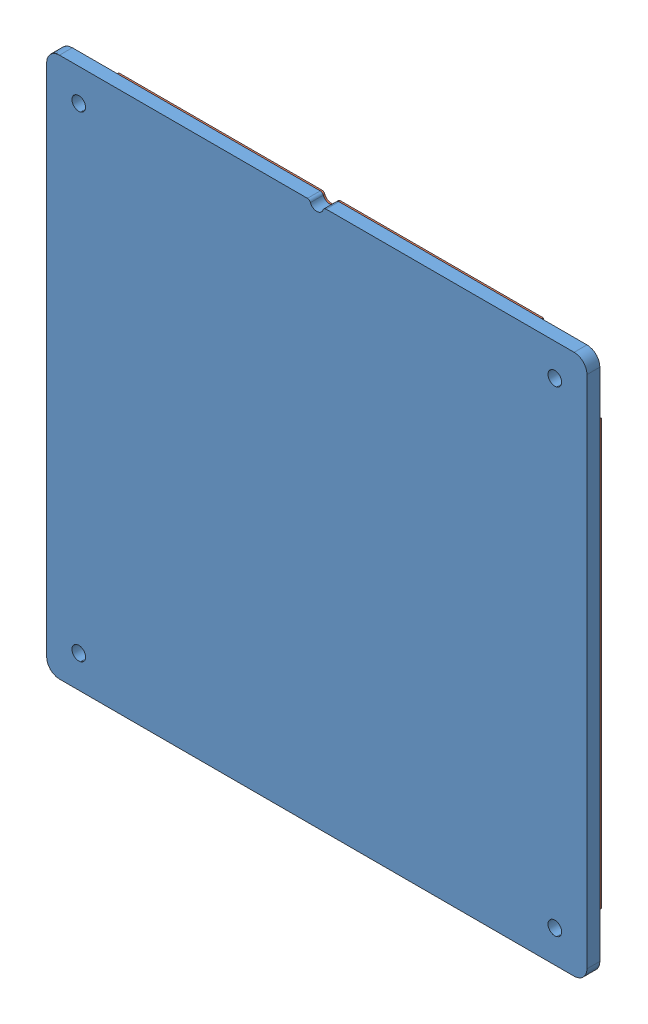
SolidWorks assembly FE-00083, configuration FE-00083-ID6. Lengths in mm.
Overall size (266.7 266.7 7.11).
2 component instances, 2 part files, 5 mates.
Components (placement in the parent):
- FE-00082-1: FE-00082 [Default] at (0 0 0.762) size (266.7 266.7 6.35)
- FE-00083-Vinyl-2: FE-00083-Vinyl [FE-00083-ID6-Vinyl] at (0 0 6.35) x (-1 0 0) z (0 0 -1) size (266.7 266.7 6.35)
Mates (geometry in assembly coordinates):
- Coincident5: coincident aligned: plane of FE-00082-1 through (133.35 -133.35 7.112) normal (1 0 0); plane of FE-00083-Vinyl-2 through (133.35 -133.35 0) normal (1 0 0)
- Coincident6: coincident aligned: plane of FE-00082-1 through (-133.35 133.35 7.112) normal (0 1 0); plane of FE-00083-Vinyl-2 through (133.35 133.35 0) normal (0 1 0)
- Symmetric1: symmetric aligned: plane of FE-00082-1 through (-133.35 -133.35 7.112) normal (0 -1 0); plane of FE-00082-1 through (-133.35 133.35 7.112) normal (0 1 0)
- Symmetric2: symmetric aligned: plane of FE-00082-1 through (133.35 -133.35 7.112) normal (1 0 0); plane of FE-00082-1 through (-133.35 -133.35 7.112) normal (-1 0 0)
- Coincident7: coincident anti-aligned: plane of FE-00083-Vinyl-2 through (0 0 0) normal (0 0 -1)
